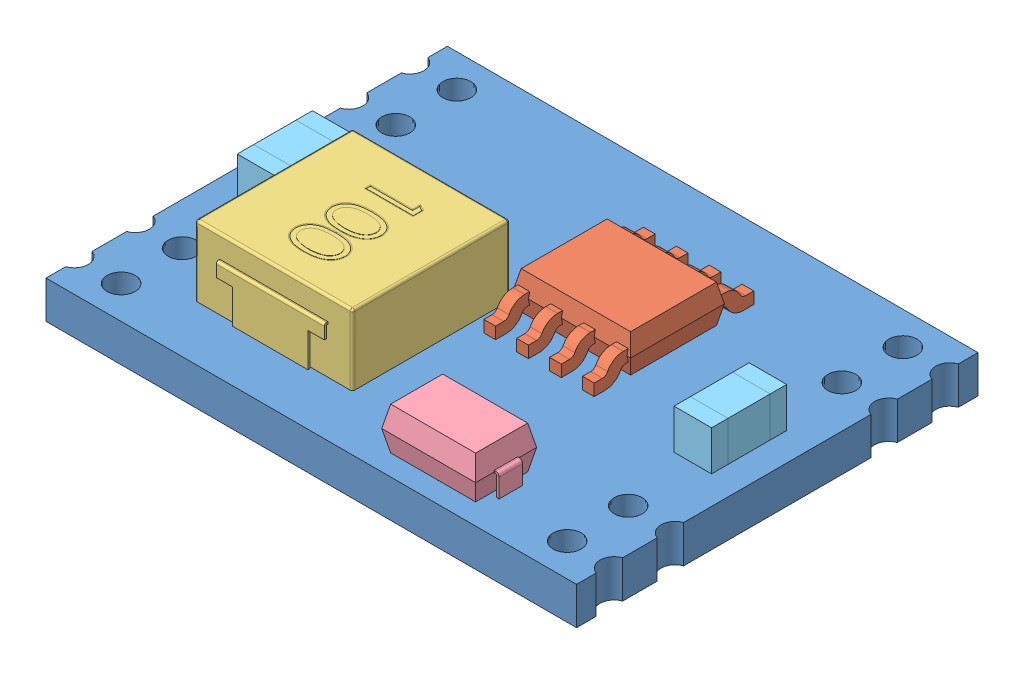
SolidWorks assembly DC-DC 5V-12V TO 3.3V STEP DOWN VOLTAGE REGULATOR POWER MODULE BOARD, configuration Default. Lengths in mm.
Overall size (22.6 4.61 17.1).
6 component instances, 5 part files, 11 mates.
Components (placement in the parent):
- PCB, DC-DC 5V-12V TO 3.3V STEP DOWN VOLTAGE REGULATOR POWER MODULE BOARD-1: PCB, DC-DC 5V-12V TO 3.3V STEP DOWN VOLTAGE REGULATOR POWER MODULE BOARD [Default] at origin size (22.6 1.6 17.1)
- IC CHIP, DC-DC 5V-12V TO 3.3V STEP DOWN VOLTAGE REGULATOR POWER MODULE BOARD-1: IC CHIP, DC-DC 5V-12V TO 3.3V STEP DOWN VOLTAGE REGULATOR POWER MODULE BOARD [Default] at (2.4 2.4 -2.15) size (5 1.6 6.8)
- CRYSTAL OSCILLATOR, DC-DC 5V-12V TO 3.3V STEP DOWN VOLTAGE REGULATOR POWER MODULE BOARD-1: CRYSTAL OSCILLATOR, DC-DC 5V-12V TO 3.3V STEP DOWN VOLTAGE REGULATOR POWER MODULE BOARD [Default] at (-3.9399 1.6 2.8558) size (6.7 3.01 7)
- SCHOTTKY DIODE, DC-DC 5V-12V TO 3.3V STEP DOWN VOLTAGE REGULATOR POWER MODULE BOARD-1: SCHOTTKY DIODE, DC-DC 5V-12V TO 3.3V STEP DOWN VOLTAGE REGULATOR POWER MODULE BOARD [Default] at (4.3 2.5 6.55) size (4.4 1.8 2.6)
- SMD RESISTOR, DC-DC 5V-12V TO 3.3V STEP DOWN VOLTAGE REGULATOR POWER MODULE BOARD-1: SMD RESISTOR, DC-DC 5V-12V TO 3.3V STEP DOWN VOLTAGE REGULATOR POWER MODULE BOARD [Default] at (9.3 1.6 0) size (1.6 1.7 3.2)
- SMD RESISTOR, DC-DC 5V-12V TO 3.3V STEP DOWN VOLTAGE REGULATOR POWER MODULE BOARD-2: SMD RESISTOR, DC-DC 5V-12V TO 3.3V STEP DOWN VOLTAGE REGULATOR POWER MODULE BOARD [Default] at (-9.3 1.6 0) x (-1 0 0) z (0 0 -1) size (1.6 1.7 3.2)
Mates (geometry in assembly coordinates):
- Coincident1: coordinate: point of assembly; point of PCB, DC-DC 5V-12V TO 3.3V STEP DOWN VOLTAGE REGULATOR POWER MODULE BOARD-1; point of assembly
- Coincident2: coincident: plane of assembly; plane of assembly; plane of PCB, DC-DC 5V-12V TO 3.3V STEP DOWN VOLTAGE REGULATOR POWER MODULE BOARD-1 through (0 1.6 0) normal (0 1 0); plane of IC CHIP, DC-DC 5V-12V TO 3.3V STEP DOWN VOLTAGE REGULATOR POWER MODULE BOARD-1 through (2.4 1.6 -2.15) normal (0 -1 0)
- Distance1: distance = 6.4 mm: plane of assembly; line of assembly; plane of PCB, DC-DC 5V-12V TO 3.3V STEP DOWN VOLTAGE REGULATOR POWER MODULE BOARD-1 through (11.3 1.6 -8.55) normal (1 0 0); line of IC CHIP, DC-DC 5V-12V TO 3.3V STEP DOWN VOLTAGE REGULATOR POWER MODULE BOARD-1 through (4.9 2.4 -0.15) axis (0 0 -1)
- Distance3: distance = 4.4 mm: line of assembly; plane of assembly; line of IC CHIP, DC-DC 5V-12V TO 3.3V STEP DOWN VOLTAGE REGULATOR POWER MODULE BOARD-1 through (4.9 2.4 -4.15) axis (-1 0 0); plane of PCB, DC-DC 5V-12V TO 3.3V STEP DOWN VOLTAGE REGULATOR POWER MODULE BOARD-1 through (-11.3 1.6 -8.55) normal (0 0 -1)
- Coincident3: coincident: plane of assembly; plane of assembly; plane of PCB, DC-DC 5V-12V TO 3.3V STEP DOWN VOLTAGE REGULATOR POWER MODULE BOARD-1 through (0 1.6 0) normal (0 1 0); plane of CRYSTAL OSCILLATOR, DC-DC 5V-12V TO 3.3V STEP DOWN VOLTAGE REGULATOR POWER MODULE BOARD-1 through (-3.9399 1.6 2.8558) normal (0 -1 0)
- Coincident4: coincident: plane of assembly; plane of assembly; plane of PCB, DC-DC 5V-12V TO 3.3V STEP DOWN VOLTAGE REGULATOR POWER MODULE BOARD-1 through (0 1.6 0) normal (0 1 0); plane of SCHOTTKY DIODE, DC-DC 5V-12V TO 3.3V STEP DOWN VOLTAGE REGULATOR POWER MODULE BOARD-1 through (4.3 1.6 6.55) normal (0 -1 0)
- Distance4: distance = 2 mm: plane of assembly; plane of assembly; plane of SCHOTTKY DIODE, DC-DC 5V-12V TO 3.3V STEP DOWN VOLTAGE REGULATOR POWER MODULE BOARD-1 through (4.3 2.5 6.55) normal (0 0 1); plane of PCB, DC-DC 5V-12V TO 3.3V STEP DOWN VOLTAGE REGULATOR POWER MODULE BOARD-1 through (-11.3 1.6 8.55) normal (0 0 1)
- Distance5: distance = 7 mm: plane of assembly; plane of assembly; plane of SCHOTTKY DIODE, DC-DC 5V-12V TO 3.3V STEP DOWN VOLTAGE REGULATOR POWER MODULE BOARD-1 through (4.3 2.5 6.55) normal (1 0 0); plane of PCB, DC-DC 5V-12V TO 3.3V STEP DOWN VOLTAGE REGULATOR POWER MODULE BOARD-1 through (11.3 1.6 -8.55) normal (1 0 0)
- Coincident5: coincident: plane of assembly; plane of assembly; plane of PCB, DC-DC 5V-12V TO 3.3V STEP DOWN VOLTAGE REGULATOR POWER MODULE BOARD-1 through (0 1.6 0) normal (0 1 0); plane of SMD RESISTOR, DC-DC 5V-12V TO 3.3V STEP DOWN VOLTAGE REGULATOR POWER MODULE BOARD-1 through (9.3 1.6 0) normal (0 -1 0)
- Coincident6: coincident: plane of assembly through (0 0 0) normal (0 0 1); plane of SMD RESISTOR, DC-DC 5V-12V TO 3.3V STEP DOWN VOLTAGE REGULATOR POWER MODULE BOARD-1 through (9.3 1.6 0) normal (0 0 1); plane of assembly
- Distance6: distance = 2 mm: plane of assembly; plane of assembly; plane of SMD RESISTOR, DC-DC 5V-12V TO 3.3V STEP DOWN VOLTAGE REGULATOR POWER MODULE BOARD-1 through (9.3 1.6 0) normal (1 0 0); plane of PCB, DC-DC 5V-12V TO 3.3V STEP DOWN VOLTAGE REGULATOR POWER MODULE BOARD-1 through (11.3 1.6 -8.55) normal (1 0 0)
